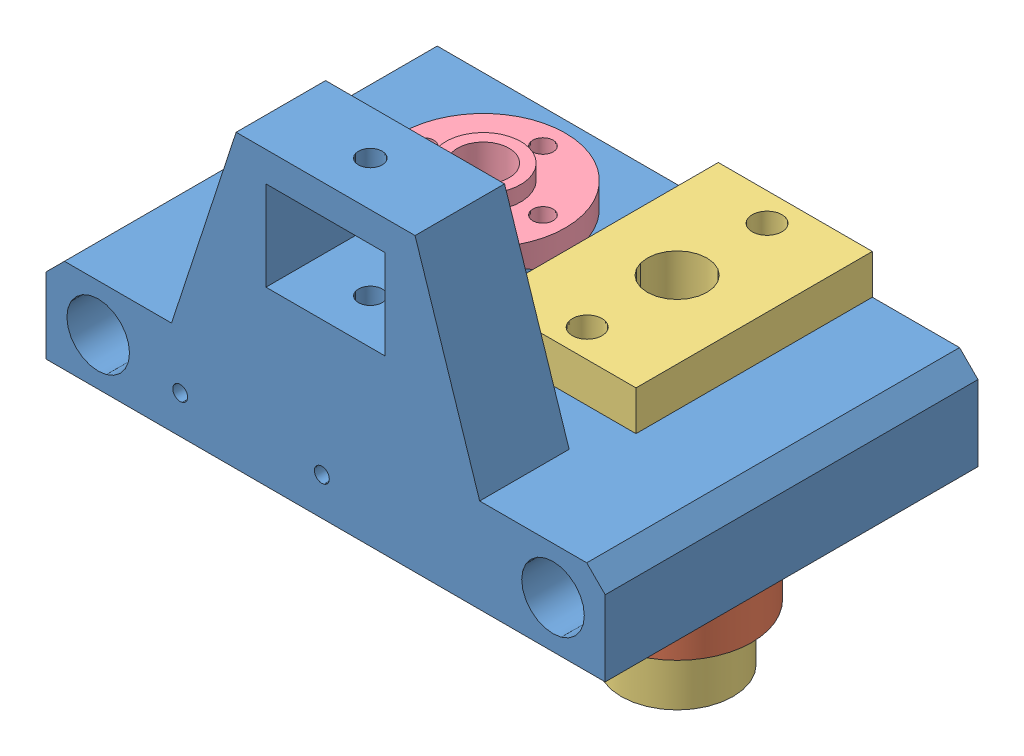
SolidWorks assembly _pulleyXAssem, configuration Default. Lengths in mm.
Overall size (75.05 66.38 50.01).
4 component instances, 4 part files, 8 mates.
Components (placement in the parent):
- xPulleyMount-1: xPulleyMount [Default] at (-23.2623 27.7759 84.2667) size (75.05 39.1 50.01)
- silverSliderBushing-1: silverSliderBushing [Default] at (27.2377 8.0259 50.1167) size (20 19.75 20)
- slider-1: slider [Default] at (16.9077 45.6959 65.9667) x (0 0 -1) z (-1 0 0) size (31.7 45.2 20.66)
- brassThing-1: brassThing [Default] at (1.2377 43.6959 50.1167) x (-1 0 0) z (0 0 1) size (22.02 10.35 22.02)
Mates (geometry in assembly coordinates):
- Coincident1: coincident anti-aligned: plane of xPulleyMount-1 through (-23.2623 27.7759 84.2667) normal (0 -1 0); plane of silverSliderBushing-1 through (27.2377 27.7759 50.1167) normal (0 1 0)
- Concentric1: concentric aligned: cylinder of xPulleyMount-1 through (27.2377 27.8759 50.1167) axis (0 -1 0) radius 7.85; cylinder of silverSliderBushing-1 through (27.2377 27.7759 50.1167) axis (0 -1 0) radius 7.9
- Coincident2: coincident anti-aligned: plane of xPulleyMount-1 through (-23.2623 40.3759 84.2667) normal (0 1 0); plane of brassThing-1 through (1.2377 40.3759 50.1167) normal (0 -1 0)
- Concentric2: concentric aligned: cylinder of xPulleyMount-1 through (1.2377 27.8759 50.1167) axis (0 -1 0) radius 5.3; circle of brassThing-1
- Concentric3: concentric anti-aligned: cylinder of xPulleyMount-1 through (27.2377 27.8759 50.1167) axis (0 -1 0) radius 7.85; cylinder of slider-1 through (27.2377 0.4959 50.1167) axis (0 1 0) radius 7.5
- Coincident3: coincident anti-aligned: plane of xPulleyMount-1 through (-23.2623 40.3759 84.2667) normal (0 1 0); plane of slider-1 through (16.9077 40.3759 65.9667) normal (0 -1 0)
- Concentric4: concentric anti-aligned: cylinder of xPulleyMount-1 through (27.2377 27.7759 38.0517) axis (0 1 0) radius 2.2; cylinder of slider-1 through (27.2377 45.6959 38.0517) axis (0 -1 0) radius 2
- Concentric5: concentric anti-aligned: cylinder of xPulleyMount-1 through (1.2377 27.7759 42.1167) axis (0 1 0) radius 1.7; cylinder of brassThing-1 through (1.2377 43.6959 42.1167) axis (0 -1 0) radius 1.37
